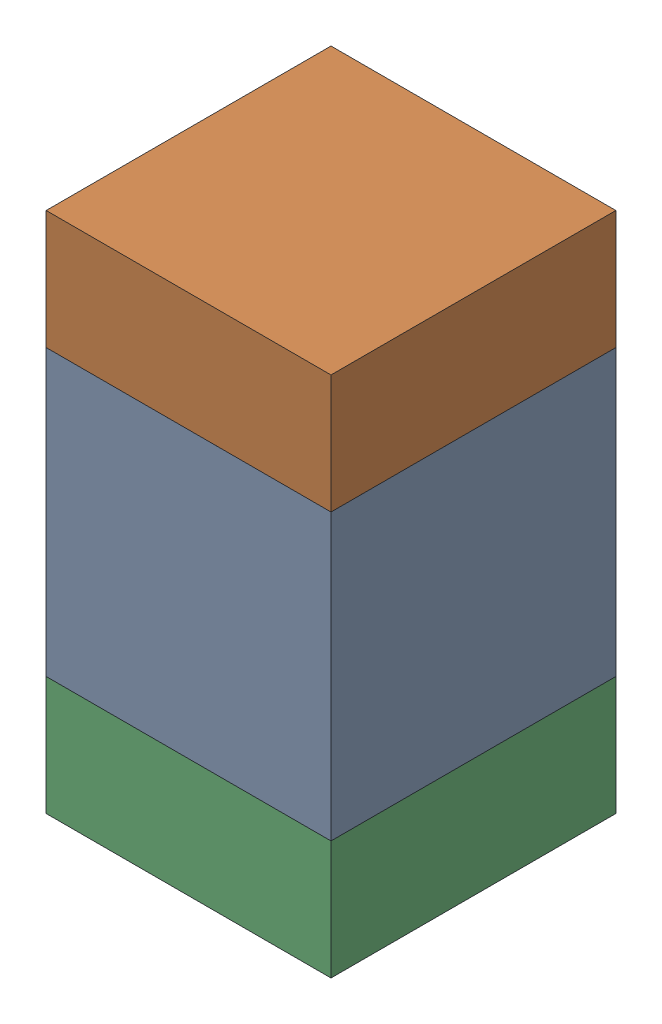
SolidWorks assembly C311_2PCB, configuration Default. Lengths in mm.
Overall size (0.6 1.1 0.6).
6 component instances, 2 part files, 0 mates.
Components (placement in the parent):
- 761606048-1: 761606048 [Default] at (144.8 100.3 0) size (0.6 0.6 0.6)
  - Extruded_9-1: Extruded_9 [Default] at origin size (0.6 0.6 0.6)
- 854785296-1: 854785296 [Default] at (144.8 100.725 0) size (0.6 0.25 0.6)
  - Extruded_10-1: Extruded_10 [Default] at origin size (0.6 0.25 0.6)
- 854785296-2: 854785296 [Default] at (144.8 99.875 0) size (0.6 0.25 0.6)
  - Extruded_10-1: Extruded_10 [Default] at origin size (0.6 0.25 0.6)
